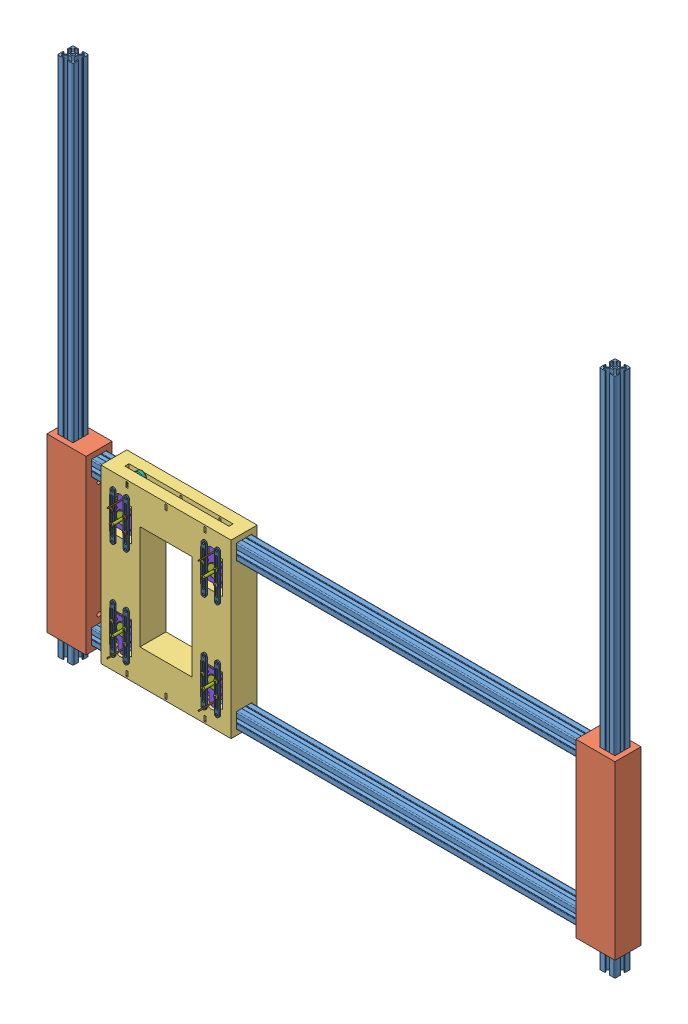
SolidWorks assembly entrega 2, configuration Predeterminado. Lengths in mm.
Overall size (1090 1000 87).
57 component instances, 12 part files, 144 mates.
Components (placement in the parent):
- riel-2: riel [Default_New2] at (-50.8053 46.5511 100) size (30 1000 30)
- soporte vertical-1: soporte vertical [Predeterminado] at (-75.8053 -748.519 100) x (0 1 0) z (1 0 0) size (330 50 75)
- riel-3: riel [Default_New2] at (969.1947 -888.519 100) x (0 -1 0) z (0 0 1) size (30 1000 30)
- riel-4: riel [Default_New2] at (969.1947 -608.519 100) x (0 -1 0) z (0 0 1) size (30 1000 30)
- carrier-1: carrier [Predeterminado] at (27.5313 -873.519 75) size (250 330 50)
- soporte rueda suelta-1: soporte rueda suelta [Predeterminado] at (77.5313 -591.519 122.5) x (-1 0 0) z (0 0 -1) size (4 5 5)
- soporte rueda suelta-2: soporte rueda suelta [Predeterminado] at (77.5313 -591.519 77.5) size (4 5 5)
- eje rueda 50mm-1: eje rueda 50mm [Predeterminado] at (77.5313 -591.519 75) size (2 2 50)
- rueda-1: rueda [Predeterminado] at (77.5313 -591.519 96) size (20 20 8)
- motor trinamics 41mm-1: motor trinamics 41mm [Predeterminado] at (65.0313 -656.019 77) size (42 42 63)
- tapa ensamble motor-1: tapa ensamble motor [Predeterminado] at (65.0313 -656.019 118) size (42 63 2)
- eje rueda 75mm-1: eje rueda 75mm [Predeterminado] at (65.0313 -624.019 75) size (2 2 75)
- tapa ensamble motor-2: tapa ensamble motor [Predeterminado] at (65.0313 -656.019 75) size (42 63 2)
- rueda-2: rueda [Predeterminado] at (65.0313 -624.019 96) size (20 20 8)
- guia motor-1: guia motor [Predeterminado] at (77.7592 -697.2469 125) size (9 94 3)
- guia motor-2: guia motor [Predeterminado] at (52.3034 -697.2469 125) size (9 94 3)
- guia motor-3: guia motor [Predeterminado] at (77.7592 -697.2469 72) size (9 94 3)
- guia motor-4: guia motor [Predeterminado] at (52.3034 -697.2469 72) size (9 94 3)
- pan head cross recess screw_iso-1: pan head cross recess screw_iso [ISO 7045 - M4 x 40 - Z - 40N] at (52.3034 -643.2911 131.1) x (0 0 -1) z (1 0 0) size (43.02 8 8)
- pan head cross recess screw_iso-2: pan head cross recess screw_iso [ISO 7045 - M4 x 40 - Z - 40N] at (77.7592 -643.2911 131.1) x (0 0 -1) z (-1 0 0) size (43.02 8 8)
- pan head cross recess screw_iso-3: pan head cross recess screw_iso [ISO 7045 - M4 x 40 - Z - 40N] at (77.7592 -668.7469 131.1) x (0 0 -1) z (1 0 0) size (43.02 8 8)
- pan head cross recess screw_iso-4: pan head cross recess screw_iso [ISO 7045 - M4 x 40 - Z - 40N] at (52.3034 -668.7469 131.1) x (0 0 -1) z (1 0 0) size (43.02 8 8)
- soporte vertical-2: soporte vertical [Predeterminado] at (1014.1947 -748.519 100) x (0 1 0) z (-1 0 0) size (330 50 75)
- riel-5: riel [Default_New2] at (989.1947 46.5511 100) size (30 1000 30)
- motor trinamics 41mm-2: motor trinamics 41mm [Predeterminado] at (240.0313 -656.019 77) size (42 42 63)
- tapa ensamble motor-3: tapa ensamble motor [Predeterminado] at (240.0313 -656.019 118) size (42 63 2)
- tapa ensamble motor-4: tapa ensamble motor [Predeterminado] at (240.0313 -656.019 75) size (42 63 2)
- eje rueda 75mm-2: eje rueda 75mm [Predeterminado] at (240.0313 -624.019 75) size (2 2 75)
- rueda-3: rueda [Predeterminado] at (240.0313 -624.019 96) size (20 20 8)
- guia motor-5: guia motor [Predeterminado] at (227.3034 -697.2469 125) size (9 94 3)
- guia motor-6: guia motor [Predeterminado] at (252.7592 -697.2469 125) size (9 94 3)
- motor trinamics 41mm-3: motor trinamics 41mm [Predeterminado] at (65.3106 -841.5202 77) x (-0.999962 0.008727 0) z (0 0 1) size (42 42 63)
- motor trinamics 41mm-4: motor trinamics 41mm [Predeterminado] at (240.0313 -841.519 77) x (-1 0 0) z (0 0 1) size (42 42 63)
- tapa ensamble motor-5: tapa ensamble motor [Predeterminado] at (65.3106 -841.5202 118) x (-0.999962 0.008727 0) z (0 0 1) size (42 63 2)
- tapa ensamble motor-6: tapa ensamble motor [Predeterminado] at (65.3106 -841.5202 75) x (-0.999962 0.008727 0) z (0 0 1) size (42 63 2)
- tapa ensamble motor-7: tapa ensamble motor [Predeterminado] at (240.0313 -841.519 118) x (-1 0 0) z (0 0 1) size (42 63 2)
- tapa ensamble motor-8: tapa ensamble motor [Predeterminado] at (240.0313 -841.519 75) x (-1 0 0) z (0 0 1) size (42 63 2)
- eje rueda 75mm-3: eje rueda 75mm [Predeterminado] at (65.0313 -873.519 75) size (2 2 75)
- eje rueda 75mm-4: eje rueda 75mm [Predeterminado] at (240.0313 -873.519 75) size (2 2 75)
- guia motor-7: guia motor [Predeterminado] at (52.3034 -884.7911 125) size (9 94 3)
- guia motor-8: guia motor [Predeterminado] at (77.7592 -884.7911 125) size (9 94 3)
- guia motor-9: guia motor [Predeterminado] at (227.3034 -884.7911 125) size (9 94 3)
- guia motor-10: guia motor [Predeterminado] at (252.7592 -884.7911 125) size (9 94 3)
- ISO 7045 - M4 x 65 - Z - 40N-5: ISO 7045 - M4 x 65 - Z - 40N [ISO 7045 - M4 x 40 - Z - 40N] at (227.3034 -643.2911 131.1) x (0 0 -1) z (1 0 0) size (68.02 8 8)
- ISO 7045 - M4 x 65 - Z - 40N-6: ISO 7045 - M4 x 65 - Z - 40N [ISO 7045 - M4 x 40 - Z - 40N] at (252.7592 -643.2911 131.1) x (0 0 -1) z (1 0 0) size (68.02 8 8)
- ISO 7045 - M4 x 65 - Z - 40N-7: ISO 7045 - M4 x 65 - Z - 40N [ISO 7045 - M4 x 40 - Z - 40N] at (227.3034 -668.7469 131.1) x (0 0 -1) z (1 0 0) size (68.02 8 8)
- ISO 7045 - M4 x 65 - Z - 40N-8: ISO 7045 - M4 x 65 - Z - 40N [ISO 7045 - M4 x 40 - Z - 40N] at (252.7592 -668.7469 131.1) x (0 0 -1) z (0.999981 -0.00619 0) size (68.02 8 8)
- ISO 7045 - M4 x 65 - Z - 40N-9: ISO 7045 - M4 x 65 - Z - 40N [ISO 7045 - M4 x 40 - Z - 40N] at (227.3034 -854.2469 131.1) x (0 0 -1) z (1 0 0) size (68.02 8 8)
- ISO 7045 - M4 x 65 - Z - 40N-10: ISO 7045 - M4 x 65 - Z - 40N [ISO 7045 - M4 x 40 - Z - 40N] at (252.7592 -854.2469 131.1) x (0 0 -1) z (1 0 0) size (68.02 8 8)
- ISO 7045 - M4 x 65 - Z - 40N-11: ISO 7045 - M4 x 65 - Z - 40N [ISO 7045 - M4 x 40 - Z - 40N] at (227.3034 -828.7911 131.1) x (0 0 -1) z (1 0 0) size (68.02 8 8)
- ISO 7045 - M4 x 65 - Z - 40N-12: ISO 7045 - M4 x 65 - Z - 40N [ISO 7045 - M4 x 40 - Z - 40N] at (252.7592 -828.7911 131.1) x (0 0 -1) z (1 0 0) size (68.02 8 8)
- ISO 7045 - M4 x 65 - Z - 40N-13: ISO 7045 - M4 x 65 - Z - 40N [ISO 7045 - M4 x 40 - Z - 40N] at (52.6942 -828.6817 131.1) x (0 0 -1) z (1 0 0) size (68.02 8 8)
- ISO 7045 - M4 x 65 - Z - 40N-14: ISO 7045 - M4 x 65 - Z - 40N [ISO 7045 - M4 x 40 - Z - 40N] at (78.1491 -828.9039 131.1) x (0 0 -1) z (1 0 0) size (68.02 8 8)
- ISO 7045 - M4 x 65 - Z - 40N-15: ISO 7045 - M4 x 65 - Z - 40N [ISO 7045 - M4 x 40 - Z - 40N] at (52.472 -854.1366 131.1) x (0 0 -1) z (1 0 0) size (68.02 8 8)
- ISO 7045 - M4 x 65 - Z - 40N-16: ISO 7045 - M4 x 65 - Z - 40N [ISO 7045 - M4 x 40 - Z - 40N] at (77.9269 -854.3587 131.1) x (0 0 -1) z (1 0 0) size (68.02 8 8)
- rueda-4: rueda [Predeterminado] at (240.0313 -873.519 96) size (20 20 8)
- rueda-5: rueda [Predeterminado] at (65.0313 -873.519 96) size (20 20 8)
Mates (geometry in assembly coordinates):
- Coincidente2: coincident anti-aligned: plane of riel-2 through (-55.7053 -953.4489 85) normal (0 0 -1); plane of soporte vertical-1 through (-65.8053 -583.519 85) normal (0 0 1)
- Coincidente3: coincident anti-aligned: plane of riel-2 through (-65.8053 -953.4489 95.1) normal (-1 0 0); plane of soporte vertical-1 through (-65.8053 -583.519 115) normal (1 0 0)
- Coincidente4: coincident anti-aligned: plane of soporte vertical-1 through (-30.8053 -903.519 115) normal (0 0 -1); plane of riel-3 through (-30.8053 -893.419 115) normal (0 0 1)
- Coincidente5: coincident anti-aligned: plane of soporte vertical-1 through (-30.8053 -873.519 115) normal (0 -1 0); plane of riel-3 through (-30.8053 -873.519 104.9) normal (0 1 0)
- Coincidente6: coincident anti-aligned: plane of soporte vertical-1 through (-30.8053 -748.519 100) normal (1 0 0); plane of riel-3 through (-30.8053 -902.619 104.9) normal (-1 0 0)
- Coincidente7: coincident anti-aligned: plane of soporte vertical-1 through (-30.8053 -748.519 100) normal (1 0 0); plane of riel-4 through (-30.8053 -622.619 104.9) normal (-1 0 0)
- Coincidente8: coincident anti-aligned: plane of soporte vertical-1 through (-30.8053 -593.519 115) normal (0 0 -1); plane of riel-4 through (-30.8053 -603.619 115) normal (0 0 1)
- Coincidente9: coincident anti-aligned: plane of soporte vertical-1 through (-30.8053 -593.519 115) normal (0 -1 0); plane of riel-4 through (-30.8053 -593.519 104.9) normal (0 1 0)
- Coincidente10: coincident anti-aligned: plane of riel-4 through (-30.8053 -603.619 115) normal (0 0 1); plane of carrier-1 through (27.5313 -593.519 115) normal (0 0 -1)
- Coincidente11: coincident anti-aligned: plane of riel-4 through (-30.8053 -593.519 104.9) normal (0 1 0); plane of carrier-1 through (27.5313 -593.519 100) normal (0 -1 0)
- Concéntrica4: concentric aligned: cylinder of carrier-1 through (77.5313 -598.519 80) axis (0 1 0) radius 1.5; cylinder of soporte rueda suelta-2 through (77.5313 -590.019 80) axis (0 1 0) radius 1.5
- Concéntrica5: concentric anti-aligned: cylinder of soporte rueda suelta-1 through (77.5313 -591.519 117.5) axis (0 0 1) radius 1; cylinder of soporte rueda suelta-2 through (77.5313 -591.519 82.5) axis (0 0 -1) radius 1
- Concéntrica6: concentric anti-aligned: cylinder of soporte rueda suelta-1 through (77.5313 -591.519 117.5) axis (0 0 1) radius 1; cylinder of eje rueda 50mm-1 through (77.5313 -591.519 125) axis (0 0 -1) radius 1
- Distancia2: distance = 0 mm aligned: plane of eje rueda 50mm-1 through (77.5313 -591.519 125) normal (0 0 1); plane of carrier-1 through (27.5313 -873.519 125) normal (0 0 1)
- Coincidente17: coincident anti-aligned: plane of carrier-1 through (52.5313 -593.519 104) normal (0 0 -1); plane of rueda-1 through (77.5313 -591.519 104) normal (0 0 1)
- Concéntrica7: concentric anti-aligned: cylinder of eje rueda 50mm-1 through (77.5313 -591.519 125) axis (0 0 -1) radius 1; cylinder of rueda-1 through (77.5313 -591.519 96) axis (0 0 1) radius 1
- Concéntrica8: concentric aligned: cylinder of motor trinamics 41mm-1 through (52.3034 -668.7469 118) axis (0 0 -1) radius 2; cylinder of tapa ensamble motor-1 through (52.3034 -668.7469 120) axis (0 0 -1) radius 2
- Coincidente18: coincident anti-aligned: plane of motor trinamics 41mm-1 through (65.0313 -656.019 118) normal (0 0 1); plane of tapa ensamble motor-1 through (65.0313 -624.019 118) normal (0 0 -1)
- Concéntrica9: concentric aligned: cylinder of motor trinamics 41mm-1 through (77.7592 -643.2911 118) axis (0 0 -1) radius 2; cylinder of tapa ensamble motor-1 through (77.7592 -643.2911 120) axis (0 0 -1) radius 2
- Coincidente19: coincident anti-aligned: plane of motor trinamics 41mm-1 through (65.0313 -656.019 77) normal (0 0 -1); plane of tapa ensamble motor-2 through (65.0313 -624.019 77) normal (0 0 1)
- Concéntrica10: concentric aligned: cylinder of motor trinamics 41mm-1 through (52.3034 -668.7469 118) axis (0 0 -1) radius 2; cylinder of tapa ensamble motor-2 through (52.3034 -668.7469 77) axis (0 0 -1) radius 2
- Concéntrica11: concentric aligned: cylinder of motor trinamics 41mm-1 through (77.7592 -643.2911 118) axis (0 0 -1) radius 2; cylinder of tapa ensamble motor-2 through (77.7592 -643.2911 77) axis (0 0 -1) radius 2
- Concéntrica12: concentric aligned: cylinder of eje rueda 75mm-1 through (65.0313 -624.019 150) axis (0 0 -1) radius 1; cylinder of tapa ensamble motor-2 through (65.0313 -624.019 77) axis (0 0 -1) radius 1
- Coincidente20: coincident aligned: plane of eje rueda 75mm-1 through (65.0313 -624.019 75) normal (0 0 -1); plane of tapa ensamble motor-2 through (65.0313 -624.019 75) normal (0 0 -1)
- Coincidente21: coincident aligned: plane of carrier-1 through (27.5313 -873.519 75) normal (0 0 -1); plane of tapa ensamble motor-2 through (65.0313 -624.019 75) normal (0 0 -1)
- Coincidente23: coincident anti-aligned: plane of carrier-1 through (52.5313 -593.519 104) normal (0 0 -1); plane of rueda-2 through (65.0313 -624.019 104) normal (0 0 1)
- Concéntrica13: concentric anti-aligned: cylinder of eje rueda 75mm-1 through (65.0313 -624.019 150) axis (0 0 -1) radius 1; cylinder of rueda-2 through (65.0313 -624.019 96) axis (0 0 1) radius 1
- Coincidente24: coincident anti-aligned: plane of carrier-1 through (27.5313 -873.519 125) normal (0 0 1); plane of guia motor-1 through (77.7592 -612.2469 125) normal (0 0 -1)
- Concéntrica15: concentric anti-aligned: cylinder of carrier-1 through (77.7592 -612.2469 125) axis (0 0 1) radius 1.65; cylinder of guia motor-1 through (77.7592 -612.2469 128) axis (0 0 -1) radius 2
- Concéntrica18: concentric anti-aligned: cylinder of carrier-1 through (77.7592 -697.2469 125) axis (0 0 1) radius 1.65; cylinder of guia motor-1 through (77.7592 -697.2469 128) axis (0 0 -1) radius 2
- Coincidente25: coincident anti-aligned: plane of carrier-1 through (27.5313 -873.519 125) normal (0 0 1); plane of guia motor-2 through (52.3034 -612.2469 125) normal (0 0 -1)
- Concéntrica19: concentric anti-aligned: cylinder of carrier-1 through (52.3034 -612.2469 125) axis (0 0 1) radius 1.65; cylinder of guia motor-2 through (52.3034 -612.2469 128) axis (0 0 -1) radius 2
- Concéntrica20: concentric anti-aligned: cylinder of carrier-1 through (52.3034 -697.2469 125) axis (0 0 1) radius 1.65; cylinder of guia motor-2 through (52.3034 -697.2469 128) axis (0 0 -1) radius 2
- Coincidente26: coincident anti-aligned: plane of carrier-1 through (27.5313 -873.519 75) normal (0 0 -1); plane of guia motor-3 through (77.7592 -612.2469 75) normal (0 0 1)
- Concéntrica21: concentric aligned: cylinder of carrier-1 through (77.7592 -612.2469 75) axis (0 0 -1) radius 1.65; cylinder of guia motor-3 through (77.7592 -612.2469 75) axis (0 0 -1) radius 2
- Concéntrica22: concentric aligned: cylinder of carrier-1 through (77.7592 -697.2469 75) axis (0 0 -1) radius 1.65; cylinder of guia motor-3 through (77.7592 -697.2469 75) axis (0 0 -1) radius 2
- Coincidente27: coincident anti-aligned: plane of carrier-1 through (27.5313 -873.519 75) normal (0 0 -1); plane of guia motor-4 through (52.3034 -612.2469 75) normal (0 0 1)
- Concéntrica23: concentric aligned: cylinder of carrier-1 through (52.3034 -612.2469 75) axis (0 0 -1) radius 1.65; cylinder of guia motor-4 through (52.3034 -612.2469 75) axis (0 0 -1) radius 2
- Concéntrica24: concentric aligned: cylinder of carrier-1 through (52.3034 -697.2469 75) axis (0 0 -1) radius 1.65; cylinder of guia motor-4 through (52.3034 -697.2469 75) axis (0 0 -1) radius 2
- Concéntrica25: concentric anti-aligned: cylinder of motor trinamics 41mm-1 through (77.7592 -643.2911 118) axis (0 0 -1) radius 2; cylinder of pan head cross recess screw_iso-2 through (77.7592 -643.2911 156.5) axis (0 0 1) radius 2
- Concéntrica26: concentric anti-aligned: cylinder of motor trinamics 41mm-1 through (52.3034 -643.2911 118) axis (0 0 -1) radius 2; cylinder of pan head cross recess screw_iso-1 through (52.3034 -643.2911 156.5) axis (0 0 1) radius 2
- Coincidente28: coincident anti-aligned: plane of guia motor-1 through (77.7592 -612.2469 128) normal (0 0 1); plane of pan head cross recess screw_iso-2 through (77.7592 -645.2911 128) normal (0 0 -1)
- Coincidente29: coincident anti-aligned: plane of guia motor-2 through (52.3034 -612.2469 128) normal (0 0 1); plane of pan head cross recess screw_iso-1 through (52.3034 -641.2911 128) normal (0 0 -1)
- Concéntrica27: concentric anti-aligned: cylinder of motor trinamics 41mm-1 through (52.3034 -668.7469 118) axis (0 0 -1) radius 2; cylinder of pan head cross recess screw_iso-4 through (52.3034 -668.7469 156.5) axis (0 0 1) radius 2
- Concéntrica28: concentric anti-aligned: cylinder of motor trinamics 41mm-1 through (77.7592 -668.7469 118) axis (0 0 -1) radius 2; cylinder of pan head cross recess screw_iso-3 through (77.7592 -668.7469 156.5) axis (0 0 1) radius 2
- Coincidente30: coincident anti-aligned: plane of guia motor-2 through (52.3034 -612.2469 128) normal (0 0 1); plane of pan head cross recess screw_iso-4 through (52.3034 -666.7469 128) normal (0 0 -1)
- Coincidente31: coincident anti-aligned: plane of guia motor-1 through (77.7592 -612.2469 128) normal (0 0 1); plane of pan head cross recess screw_iso-3 through (77.7592 -666.7469 128) normal (0 0 -1)
- Coincidente33: coincident anti-aligned: plane of riel-4 through (-30.8053 -99.1491 85) normal (0 0 -1); plane of soporte vertical-2 through (969.1947 -79.2491 85) normal (0 0 1)
- Coincidente34: coincident anti-aligned: plane of riel-4 through (969.1947 -108.3491 104.9) normal (1 0 0); plane of soporte vertical-2 through (969.1947 -234.2491 100) normal (-1 0 0)
- Coincidente35: coincident anti-aligned: plane of riel-4 through (-30.8053 -79.2491 104.9) normal (0 1 0); plane of soporte vertical-2 through (969.1947 -79.2491 85) normal (0 -1 0)
- Coincidente36: coincident anti-aligned: plane of riel-4 through (-30.8053 -603.619 85) normal (0 0 -1); plane of soporte vertical-2 through (969.1947 -593.519 85) normal (0 0 1)
- Coincidente37: coincident anti-aligned: plane of riel-4 through (969.1947 -622.619 104.9) normal (1 0 0); plane of soporte vertical-2 through (969.1947 -748.519 100) normal (-1 0 0)
- Coincidente38: coincident anti-aligned: plane of riel-4 through (-30.8053 -593.519 95.1) normal (0 1 0); plane of soporte vertical-2 through (969.1947 -593.519 85) normal (0 -1 0)
- Distancia3: distance = 0 mm aligned: plane of riel-5 through (1003.2947 46.5511 104.9) normal (0 1 0); plane of riel-2 through (-36.7053 46.5511 104.9) normal (0 1 0)
- Coincidente40: coincident anti-aligned: plane of soporte vertical-2 through (1004.1947 -583.519 115) normal (0 0 -1); plane of riel-5 through (984.2947 -953.4489 115) normal (0 0 1)
- Coincidente41: coincident anti-aligned: plane of soporte vertical-2 through (1004.1947 -583.519 85) normal (-1 0 0); plane of riel-5 through (1004.1947 -953.4489 104.9) normal (1 0 0)
- Coincidente42: coincident anti-aligned: plane of motor trinamics 41mm-2 through (240.0313 -656.019 118) normal (0 0 1); plane of tapa ensamble motor-3 through (240.0313 -624.019 118) normal (0 0 -1)
- Concéntrica29: concentric aligned: cylinder of motor trinamics 41mm-2 through (227.3034 -643.2911 118) axis (0 0 -1) radius 2; cylinder of tapa ensamble motor-3 through (227.3034 -643.2911 120) axis (0 0 -1) radius 2
- Concéntrica30: concentric aligned: cylinder of motor trinamics 41mm-2 through (252.7592 -668.7469 118) axis (0 0 -1) radius 2; cylinder of tapa ensamble motor-3 through (252.7592 -668.7469 120) axis (0 0 -1) radius 2
- Concéntrica31: concentric aligned: cylinder of tapa ensamble motor-3 through (240.0313 -624.019 120) axis (0 0 -1) radius 1; cylinder of eje rueda 75mm-2 through (240.0313 -624.019 150) axis (0 0 -1) radius 1
- Coincidente43: coincident anti-aligned: plane of motor trinamics 41mm-2 through (240.0313 -656.019 77) normal (0 0 -1); plane of tapa ensamble motor-4 through (240.0313 -624.019 77) normal (0 0 1)
- Concéntrica32: concentric aligned: cylinder of motor trinamics 41mm-2 through (227.3034 -643.2911 118) axis (0 0 -1) radius 2; cylinder of tapa ensamble motor-4 through (227.3034 -643.2911 77) axis (0 0 -1) radius 2
- Concéntrica33: concentric aligned: cylinder of motor trinamics 41mm-2 through (252.7592 -668.7469 118) axis (0 0 -1) radius 2; cylinder of tapa ensamble motor-4 through (252.7592 -668.7469 77) axis (0 0 -1) radius 2
- Coincidente44: coincident aligned: plane of tapa ensamble motor-4 through (240.0313 -624.019 75) normal (0 0 -1); plane of eje rueda 75mm-2 through (240.0313 -624.019 75) normal (0 0 -1)
- Coincidente45: coincident aligned: plane of carrier-1 through (27.5313 -873.519 75) normal (0 0 -1); plane of tapa ensamble motor-4 through (240.0313 -624.019 75) normal (0 0 -1)
- Coincidente47: coincident anti-aligned: plane of carrier-1 through (52.5313 -593.519 104) normal (0 0 -1); plane of rueda-3 through (240.0313 -624.019 104) normal (0 0 1)
- Concéntrica35: concentric anti-aligned: cylinder of eje rueda 75mm-2 through (240.0313 -624.019 150) axis (0 0 -1) radius 1; cylinder of rueda-3 through (240.0313 -624.019 96) axis (0 0 1) radius 1
- Coincidente48: coincident anti-aligned: plane of carrier-1 through (27.5313 -873.519 125) normal (0 0 1); plane of guia motor-5 through (227.3034 -612.2469 125) normal (0 0 -1)
- Concéntrica36: concentric anti-aligned: cylinder of carrier-1 through (227.3034 -612.2469 125) axis (0 0 1) radius 1.65; cylinder of guia motor-5 through (227.3034 -612.2469 128) axis (0 0 -1) radius 2
- Concéntrica37: concentric anti-aligned: cylinder of carrier-1 through (227.3034 -697.2469 125) axis (0 0 1) radius 1.65; cylinder of guia motor-5 through (227.3034 -697.2469 128) axis (0 0 -1) radius 2
- Coincidente49: coincident anti-aligned: plane of carrier-1 through (27.5313 -873.519 125) normal (0 0 1); plane of guia motor-6 through (252.7592 -612.2469 125) normal (0 0 -1)
- Concéntrica38: concentric anti-aligned: cylinder of carrier-1 through (252.7592 -612.2469 125) axis (0 0 1) radius 1.65; cylinder of guia motor-6 through (252.7592 -612.2469 128) axis (0 0 -1) radius 2
- Concéntrica39: concentric anti-aligned: cylinder of carrier-1 through (252.7592 -697.2469 125) axis (0 0 1) radius 1.65; cylinder of guia motor-6 through (252.7592 -697.2469 128) axis (0 0 -1) radius 2
- Coincidente50: coincident anti-aligned: plane of motor trinamics 41mm-3 through (65.3106 -841.5202 118) normal (0 0 1); plane of tapa ensamble motor-5 through (65.0313 -873.519 118) normal (0 0 -1)
- Coincidente51: coincident anti-aligned: plane of motor trinamics 41mm-3 through (65.3106 -841.5202 77) normal (0 0 -1); plane of tapa ensamble motor-6 through (65.0313 -873.519 77) normal (0 0 1)
- Concéntrica40: concentric aligned: cylinder of motor trinamics 41mm-3 through (52.472 -854.1366 118) axis (0 0 -1) radius 2; cylinder of tapa ensamble motor-6 through (52.472 -854.1366 77) axis (0 0 -1) radius 2
- Concéntrica41: concentric aligned: cylinder of motor trinamics 41mm-3 through (78.1491 -828.9039 118) axis (0 0 -1) radius 2; cylinder of tapa ensamble motor-6 through (78.1491 -828.9039 77) axis (0 0 -1) radius 2
- Concéntrica42: concentric aligned: cylinder of motor trinamics 41mm-3 through (52.472 -854.1366 118) axis (0 0 -1) radius 2; cylinder of tapa ensamble motor-5 through (52.472 -854.1366 120) axis (0 0 -1) radius 2
- Concéntrica43: concentric aligned: cylinder of motor trinamics 41mm-3 through (78.1491 -828.9039 118) axis (0 0 -1) radius 2; cylinder of tapa ensamble motor-5 through (78.1491 -828.9039 120) axis (0 0 -1) radius 2
- Coincidente52: coincident anti-aligned: plane of motor trinamics 41mm-4 through (240.0313 -841.519 77) normal (0 0 -1); plane of tapa ensamble motor-8 through (240.0313 -873.519 77) normal (0 0 1)
- Concéntrica44: concentric aligned: cylinder of motor trinamics 41mm-4 through (252.7592 -828.7911 118) axis (0 0 -1) radius 2; cylinder of tapa ensamble motor-8 through (252.7592 -828.7911 77) axis (0 0 -1) radius 2
- Concéntrica45: concentric aligned: cylinder of motor trinamics 41mm-4 through (227.3034 -854.2469 118) axis (0 0 -1) radius 2; cylinder of tapa ensamble motor-8 through (227.3034 -854.2469 77) axis (0 0 -1) radius 2
- Coincidente53: coincident anti-aligned: plane of motor trinamics 41mm-4 through (240.0313 -841.519 118) normal (0 0 1); plane of tapa ensamble motor-7 through (240.0313 -873.519 118) normal (0 0 -1)
- Concéntrica46: concentric aligned: cylinder of motor trinamics 41mm-4 through (252.7592 -854.2469 118) axis (0 0 -1) radius 2; cylinder of tapa ensamble motor-7 through (252.7592 -854.2469 120) axis (0 0 -1) radius 2
- Concéntrica47: concentric aligned: cylinder of motor trinamics 41mm-4 through (227.3034 -828.7911 118) axis (0 0 -1) radius 2; cylinder of tapa ensamble motor-7 through (227.3034 -828.7911 120) axis (0 0 -1) radius 2
- Coincidente54: coincident aligned: plane of carrier-1 through (27.5313 -873.519 75) normal (0 0 -1); plane of tapa ensamble motor-6 through (65.0313 -873.519 75) normal (0 0 -1)
- Coincidente55: coincident aligned: plane of carrier-1 through (27.5313 -873.519 75) normal (0 0 -1); plane of tapa ensamble motor-8 through (240.0313 -873.519 75) normal (0 0 -1)
- Concéntrica48: concentric aligned: cylinder of tapa ensamble motor-5 through (65.0313 -873.519 120) axis (0 0 -1) radius 1; cylinder of eje rueda 75mm-3 through (65.0313 -873.519 150) axis (0 0 -1) radius 1
- Coincidente56: coincident aligned: plane of tapa ensamble motor-6 through (65.0313 -873.519 75) normal (0 0 -1); plane of eje rueda 75mm-3 through (65.0313 -873.519 75) normal (0 0 -1)
- Concéntrica49: concentric aligned: cylinder of tapa ensamble motor-8 through (240.0313 -873.519 77) axis (0 0 -1) radius 1; cylinder of eje rueda 75mm-4 through (240.0313 -873.519 150) axis (0 0 -1) radius 1
- Coincidente57: coincident aligned: plane of tapa ensamble motor-8 through (240.0313 -873.519 75) normal (0 0 -1); plane of eje rueda 75mm-4 through (240.0313 -873.519 75) normal (0 0 -1)
- Concéntrica50: concentric anti-aligned: cylinder of carrier-1 through (65.0313 -873.519 75) axis (0 0 1) radius 10; cylinder of eje rueda 75mm-3 through (65.0313 -873.519 150) axis (0 0 -1) radius 1
- Concéntrica51: concentric anti-aligned: cylinder of carrier-1 through (240.0313 -873.519 75) axis (0 0 1) radius 10; cylinder of eje rueda 75mm-4 through (240.0313 -873.519 150) axis (0 0 -1) radius 1
- Coincidente58: coincident anti-aligned: plane of carrier-1 through (27.5313 -873.519 125) normal (0 0 1); plane of guia motor-8 through (77.7592 -799.7911 125) normal (0 0 -1)
- Concéntrica52: concentric anti-aligned: cylinder of carrier-1 through (77.7592 -799.7911 125) axis (0 0 1) radius 1.65; cylinder of guia motor-8 through (77.7592 -799.7911 128) axis (0 0 -1) radius 2
- Concéntrica53: concentric anti-aligned: cylinder of carrier-1 through (77.7592 -884.7911 125) axis (0 0 1) radius 1.65; cylinder of guia motor-8 through (77.7592 -884.7911 128) axis (0 0 -1) radius 2
- Coincidente59: coincident anti-aligned: plane of carrier-1 through (27.5313 -873.519 125) normal (0 0 1); plane of guia motor-7 through (52.3034 -799.7911 125) normal (0 0 -1)
- Concéntrica54: concentric anti-aligned: cylinder of carrier-1 through (52.3034 -884.7911 125) axis (0 0 1) radius 1.65; cylinder of guia motor-7 through (52.3034 -884.7911 128) axis (0 0 -1) radius 2
- Concéntrica55: concentric anti-aligned: cylinder of carrier-1 through (52.3034 -799.7911 125) axis (0 0 1) radius 1.65; cylinder of guia motor-7 through (52.3034 -799.7911 128) axis (0 0 -1) radius 2
- Coincidente60: coincident anti-aligned: plane of carrier-1 through (27.5313 -873.519 125) normal (0 0 1); plane of guia motor-9 through (227.3034 -799.7911 125) normal (0 0 -1)
- Concéntrica56: concentric anti-aligned: cylinder of carrier-1 through (227.3034 -884.7911 125) axis (0 0 1) radius 1.65; cylinder of guia motor-9 through (227.3034 -884.7911 128) axis (0 0 -1) radius 2
- Concéntrica57: concentric anti-aligned: cylinder of carrier-1 through (227.3034 -799.7911 125) axis (0 0 1) radius 1.65; cylinder of guia motor-9 through (227.3034 -799.7911 128) axis (0 0 -1) radius 2
- Coincidente61: coincident anti-aligned: plane of carrier-1 through (27.5313 -873.519 125) normal (0 0 1); plane of guia motor-10 through (252.7592 -799.7911 125) normal (0 0 -1)
- Concéntrica58: concentric anti-aligned: cylinder of carrier-1 through (252.7592 -799.7911 125) axis (0 0 1) radius 1.65; cylinder of guia motor-10 through (252.7592 -799.7911 128) axis (0 0 -1) radius 2
- Concéntrica59: concentric anti-aligned: cylinder of carrier-1 through (252.7592 -884.7911 125) axis (0 0 1) radius 1.65; cylinder of guia motor-10 through (252.7592 -884.7911 128) axis (0 0 -1) radius 2
- Tangente1: tangent anti-aligned: plane of guia motor-1 through (75.7592 -622.2469 128) normal (1 0 0); cylinder of pan head cross recess screw_iso-2 through (77.7592 -643.2911 156.5) axis (0 0 1) radius 2
- Tangente2: tangent anti-aligned: plane of guia motor-2 through (50.3034 -622.2469 128) normal (1 0 0); cylinder of pan head cross recess screw_iso-4 through (52.3034 -668.7469 156.5) axis (0 0 1) radius 2
- Distancia4: distance = 0.5 mm: cylinder of eje rueda 75mm-1 through (65.0313 -624.019 150) axis (0 0 -1) radius 1; cylinder of carrier-1 through (65.0313 -623.519 75) axis (0 0 1) radius 10
- Concéntrica62: concentric anti-aligned: cylinder of motor trinamics 41mm-2 through (252.7592 -668.7469 118) axis (0 0 -1) radius 2; cylinder of ISO 7045 - M4 x 65 - Z - 40N-8 through (252.7592 -668.7469 156.5) axis (0 0 1) radius 2
- Coincidente62: coincident anti-aligned: plane of guia motor-6 through (252.7592 -612.2469 128) normal (0 0 1); plane of ISO 7045 - M4 x 65 - Z - 40N-8 through (252.7716 -666.747 128) normal (0 0 -1)
- Tangente3: tangent anti-aligned: plane of guia motor-6 through (250.7592 -622.2469 128) normal (1 0 0); cylinder of ISO 7045 - M4 x 65 - Z - 40N-8 through (252.7592 -668.7469 156.5) axis (0 0 1) radius 2
- Coincidente63: coincident anti-aligned: plane of guia motor-5 through (227.3034 -612.2469 128) normal (0 0 1); plane of ISO 7045 - M4 x 65 - Z - 40N-5 through (227.3034 -641.2911 128) normal (0 0 -1)
- Concéntrica64: concentric anti-aligned: cylinder of motor trinamics 41mm-2 through (227.3034 -643.2911 118) axis (0 0 -1) radius 2; cylinder of ISO 7045 - M4 x 65 - Z - 40N-5 through (227.3034 -643.2911 156.5) axis (0 0 1) radius 2
- Tangente4: tangent anti-aligned: plane of guia motor-5 through (225.3034 -622.2469 128) normal (1 0 0); cylinder of ISO 7045 - M4 x 65 - Z - 40N-5 through (227.3034 -643.2911 156.5) axis (0 0 1) radius 2
- Distancia11: distance = 0.5 mm: cylinder of tapa ensamble motor-3 through (240.0313 -624.019 120) axis (0 0 -1) radius 10; cylinder of carrier-1 through (240.0313 -623.519 75) axis (0 0 1) radius 10
- Coincidente64: coincident anti-aligned: plane of guia motor-6 through (252.7592 -612.2469 128) normal (0 0 1); plane of ISO 7045 - M4 x 65 - Z - 40N-6 through (252.7592 -641.2911 128) normal (0 0 -1)
- Concéntrica69: concentric anti-aligned: cylinder of motor trinamics 41mm-2 through (252.7592 -643.2911 118) axis (0 0 -1) radius 2; cylinder of ISO 7045 - M4 x 65 - Z - 40N-6 through (252.7592 -643.2911 156.5) axis (0 0 1) radius 2
- Concéntrica70: concentric anti-aligned: cylinder of motor trinamics 41mm-2 through (227.3034 -668.7469 118) axis (0 0 -1) radius 2; cylinder of ISO 7045 - M4 x 65 - Z - 40N-7 through (227.3034 -668.7469 156.5) axis (0 0 1) radius 2
- Coincidente65: coincident anti-aligned: plane of guia motor-5 through (227.3034 -612.2469 128) normal (0 0 1); plane of ISO 7045 - M4 x 65 - Z - 40N-7 through (227.3034 -666.7469 128) normal (0 0 -1)
- Coincidente66: coincident anti-aligned: plane of guia motor-10 through (252.7592 -799.7911 128) normal (0 0 1); plane of ISO 7045 - M4 x 65 - Z - 40N-12 through (252.7592 -826.7911 128) normal (0 0 -1)
- Concéntrica71: concentric anti-aligned: cylinder of motor trinamics 41mm-4 through (252.7592 -828.7911 118) axis (0 0 -1) radius 2; cylinder of ISO 7045 - M4 x 65 - Z - 40N-12 through (252.7592 -828.7911 156.5) axis (0 0 1) radius 2
- Coincidente67: coincident anti-aligned: plane of guia motor-9 through (227.3034 -799.7911 128) normal (0 0 1); plane of ISO 7045 - M4 x 65 - Z - 40N-11 through (227.3034 -826.7911 128) normal (0 0 -1)
- Concéntrica72: concentric anti-aligned: cylinder of motor trinamics 41mm-4 through (227.3034 -828.7911 118) axis (0 0 -1) radius 2; cylinder of ISO 7045 - M4 x 65 - Z - 40N-11 through (227.3034 -828.7911 156.5) axis (0 0 1) radius 2
- Coincidente68: coincident anti-aligned: plane of guia motor-10 through (252.7592 -799.7911 128) normal (0 0 1); plane of ISO 7045 - M4 x 65 - Z - 40N-10 through (252.7592 -852.2469 128) normal (0 0 -1)
- Concéntrica73: concentric anti-aligned: cylinder of motor trinamics 41mm-4 through (252.7592 -854.2469 118) axis (0 0 -1) radius 2; cylinder of ISO 7045 - M4 x 65 - Z - 40N-10 through (252.7592 -854.2469 156.5) axis (0 0 1) radius 2
- Coincidente69: coincident anti-aligned: plane of guia motor-9 through (227.3034 -799.7911 128) normal (0 0 1); plane of ISO 7045 - M4 x 65 - Z - 40N-9 through (227.3034 -852.2469 128) normal (0 0 -1)
- Concéntrica74: concentric anti-aligned: cylinder of motor trinamics 41mm-4 through (227.3034 -854.2469 118) axis (0 0 -1) radius 2; cylinder of ISO 7045 - M4 x 65 - Z - 40N-9 through (227.3034 -854.2469 156.5) axis (0 0 1) radius 2
- Tangente5: tangent anti-aligned: plane of guia motor-10 through (250.7592 -809.7911 128) normal (1 0 0); cylinder of ISO 7045 - M4 x 65 - Z - 40N-12 through (252.7592 -828.7911 156.5) axis (0 0 1) radius 2
- Tangente6: tangent anti-aligned: plane of guia motor-9 through (225.3034 -809.7911 128) normal (1 0 0); cylinder of ISO 7045 - M4 x 65 - Z - 40N-9 through (227.3034 -854.2469 156.5) axis (0 0 1) radius 2
- Tangente8: tangent anti-aligned: plane of guia motor-10 through (250.7592 -809.7911 128) normal (1 0 0); cylinder of ISO 7045 - M4 x 65 - Z - 40N-12 through (252.7592 -828.7911 156.5) axis (0 0 1) radius 2
- Coincidente70: coincident anti-aligned: plane of guia motor-8 through (77.7592 -799.7911 128) normal (0 0 1); plane of ISO 7045 - M4 x 65 - Z - 40N-14 through (78.1491 -826.9039 128) normal (0 0 -1)
- Concéntrica75: concentric anti-aligned: cylinder of motor trinamics 41mm-3 through (78.1491 -828.9039 118) axis (0 0 -1) radius 2; cylinder of ISO 7045 - M4 x 65 - Z - 40N-14 through (78.1491 -828.9039 156.5) axis (0 0 1) radius 2
- Coincidente71: coincident anti-aligned: plane of guia motor-7 through (52.3034 -799.7911 128) normal (0 0 1); plane of ISO 7045 - M4 x 65 - Z - 40N-13 through (52.6942 -826.6817 128) normal (0 0 -1)
- Concéntrica76: concentric anti-aligned: cylinder of motor trinamics 41mm-3 through (52.6942 -828.6817 118) axis (0 0 -1) radius 2; cylinder of ISO 7045 - M4 x 65 - Z - 40N-13 through (52.6942 -828.6817 156.5) axis (0 0 1) radius 2
- Coincidente72: coincident anti-aligned: plane of guia motor-8 through (77.7592 -799.7911 128) normal (0 0 1); plane of ISO 7045 - M4 x 65 - Z - 40N-16 through (77.9269 -852.3587 128) normal (0 0 -1)
- Concéntrica77: concentric anti-aligned: cylinder of motor trinamics 41mm-3 through (77.9269 -854.3587 118) axis (0 0 -1) radius 2; cylinder of ISO 7045 - M4 x 65 - Z - 40N-16 through (77.9269 -854.3587 156.5) axis (0 0 1) radius 2
- Coincidente73: coincident anti-aligned: plane of guia motor-7 through (52.3034 -799.7911 128) normal (0 0 1); plane of ISO 7045 - M4 x 65 - Z - 40N-15 through (52.472 -852.1366 128) normal (0 0 -1)
- Concéntrica78: concentric anti-aligned: cylinder of motor trinamics 41mm-3 through (52.472 -854.1366 118) axis (0 0 -1) radius 2; cylinder of ISO 7045 - M4 x 65 - Z - 40N-15 through (52.472 -854.1366 156.5) axis (0 0 1) radius 2
- Coincidente74: coincident anti-aligned: plane of carrier-1 through (52.5313 -903.519 104) normal (0 0 -1); plane of rueda-4 through (240.0313 -873.519 104) normal (0 0 1)
- Concéntrica79: concentric anti-aligned: cylinder of eje rueda 75mm-4 through (240.0313 -873.519 150) axis (0 0 -1) radius 1; cylinder of rueda-4 through (240.0313 -873.519 96) axis (0 0 1) radius 1
- Coincidente75: coincident anti-aligned: plane of carrier-1 through (52.5313 -903.519 104) normal (0 0 -1); plane of rueda-5 through (65.0313 -873.519 104) normal (0 0 1)
- Concéntrica80: concentric anti-aligned: cylinder of eje rueda 75mm-3 through (65.0313 -873.519 150) axis (0 0 -1) radius 1; cylinder of rueda-5 through (65.0313 -873.519 96) axis (0 0 1) radius 1
- Distancia12: distance = 2.5 mm anti-aligned: plane of carrier-1 through (79.5313 -596.519 125) normal (0 1 0); plane of soporte rueda suelta-1 through (79.5313 -594.019 117.5) normal (0 -1 0)
- Coincidente77: coincident anti-aligned: plane of carrier-1 through (79.5313 -586.519 75) normal (-1 0 0); plane of soporte rueda suelta-1 through (79.5313 -594.019 117.5) normal (1 0 0)
